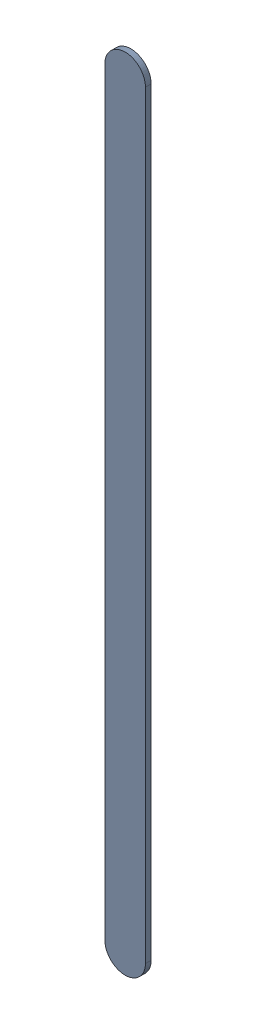
SolidWorks assembly Track (16.7mm,27.749mm)(16.7mm,32.5mm) on Top Layer, configuration Predeterminado. Lengths in mm.
Overall size (0.25 5.01 0.04).
2 component instances, 1 part files, 0 mates.
Components (placement in the parent):
- Track (16.7mm,27.749mm)(16.7mm,32.5mm) on Top Layer-1-1: Track (16.7mm,27.749mm)(16.7mm,32.5mm) on Top Layer-1 [Predeterminado] at (-68.317 -44.187 -0.0457) size (0.25 5.01 0.04)
  - Track (16.7mm,27.749mm)(16.7mm,32.5mm) on Top Layer-Part-1-1: Track (16.7mm,27.749mm)(16.7mm,32.5mm) on Top Layer-Part-1 [Predeterminado] at origin size (0.25 5.01 0.04)
